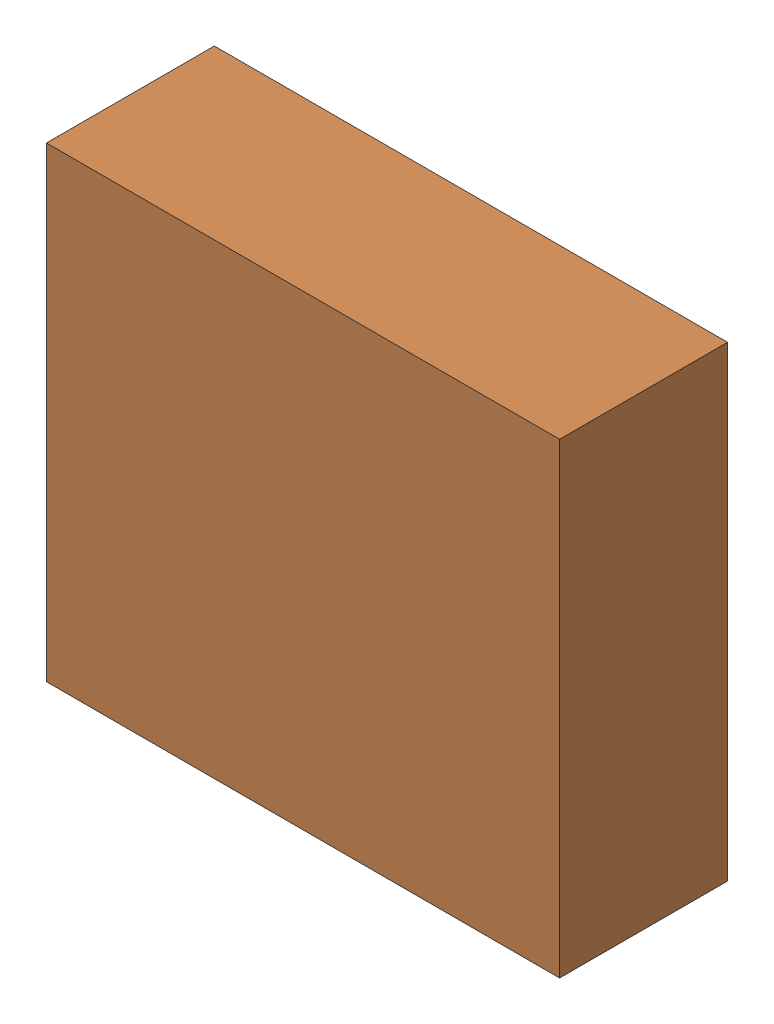
SolidWorks assembly U7, configuration Default. Lengths in mm.
Overall size (2.75 2.5 0.93).
4 component instances, 2 part files, 0 mates.
Components (placement in the parent):
- 756964248-1: 756964248 [Default] at (21.65 54.2999 -0.6115) x (0 1 0) z (0 0 -1) size (0.2 0.2 0.78)
  - Cylinder (2)-1: Cylinder (2) [Default] at origin size (0.2 0.2 0.78)
- 676623520-1: 676623520 [Default] at (20.625 53.5 -1.3615) size (2.75 2.5 0.9)
  - Extruded (8)-1: Extruded (8) [Default] at origin size (2.75 2.5 0.9)
